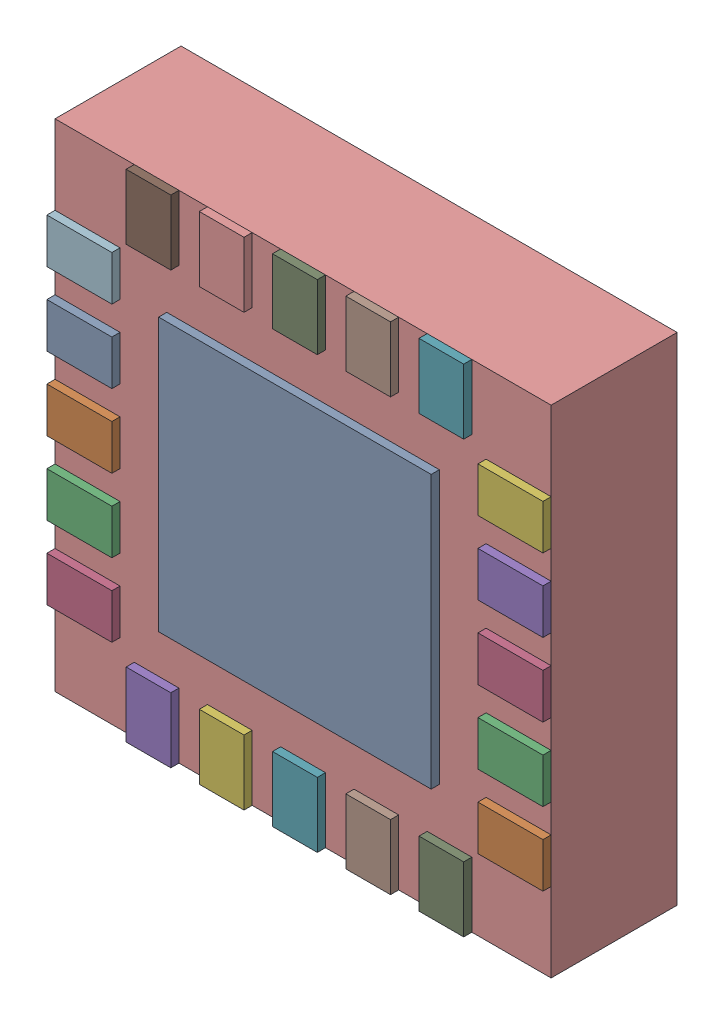
SolidWorks assembly U4, configuration Default. Lengths in mm.
Overall size (3.1 3.1 0.84).
24 component instances, 23 part files, 0 mates.
Components (placement in the parent):
- U4-subassembly-1-1: U4-subassembly-1 [Default] at (0.0001 0 -1.6307) x (0 1 0) z (0 0 -1) size (3.1 3.1 0.84)
  - VQFN20_3X3_MCH-1: VQFN20_3X3_MCH [Default] at origin size (1.7 1.7 0.05)
  - VQFN20_3X3_MCH-1-1: VQFN20_3X3_MCH-1 [Default] at origin size (0.28 0.41 0.05)
  - VQFN20_3X3_MCH-2-1: VQFN20_3X3_MCH-2 [Default] at origin size (0.28 0.41 0.05)
  - VQFN20_3X3_MCH-3-1: VQFN20_3X3_MCH-3 [Default] at origin size (0.28 0.41 0.05)
  - VQFN20_3X3_MCH-4-1: VQFN20_3X3_MCH-4 [Default] at origin size (0.28 0.41 0.05)
  - VQFN20_3X3_MCH-5-1: VQFN20_3X3_MCH-5 [Default] at origin size (0.28 0.41 0.05)
  - VQFN20_3X3_MCH-6-1: VQFN20_3X3_MCH-6 [Default] at origin size (0.41 0.28 0.05)
  - VQFN20_3X3_MCH-7-1: VQFN20_3X3_MCH-7 [Default] at origin size (0.41 0.28 0.05)
  - VQFN20_3X3_MCH-8-1: VQFN20_3X3_MCH-8 [Default] at origin size (0.41 0.28 0.05)
  - VQFN20_3X3_MCH-9-1: VQFN20_3X3_MCH-9 [Default] at origin size (0.41 0.28 0.05)
  - VQFN20_3X3_MCH-10-1: VQFN20_3X3_MCH-10 [Default] at origin size (0.41 0.28 0.05)
  - VQFN20_3X3_MCH-11-1: VQFN20_3X3_MCH-11 [Default] at origin size (0.28 0.41 0.05)
  - VQFN20_3X3_MCH-12-1: VQFN20_3X3_MCH-12 [Default] at origin size (0.28 0.41 0.05)
  - VQFN20_3X3_MCH-13-1: VQFN20_3X3_MCH-13 [Default] at origin size (0.28 0.41 0.05)
  - VQFN20_3X3_MCH-14-1: VQFN20_3X3_MCH-14 [Default] at origin size (0.28 0.41 0.05)
  - VQFN20_3X3_MCH-15-1: VQFN20_3X3_MCH-15 [Default] at origin size (0.28 0.41 0.05)
  - VQFN20_3X3_MCH-16-1: VQFN20_3X3_MCH-16 [Default] at origin size (0.41 0.28 0.05)
  - VQFN20_3X3_MCH-17-1: VQFN20_3X3_MCH-17 [Default] at origin size (0.41 0.28 0.05)
  - VQFN20_3X3_MCH-18-1: VQFN20_3X3_MCH-18 [Default] at origin size (0.41 0.28 0.05)
  - VQFN20_3X3_MCH-19-1: VQFN20_3X3_MCH-19 [Default] at origin size (0.41 0.28 0.05)
  - VQFN20_3X3_MCH-20-1: VQFN20_3X3_MCH-20 [Default] at origin size (0.41 0.28 0.05)
  - VQFN20_3X3_MCH-21-1: VQFN20_3X3_MCH-21 [Default] at origin size (3.1 3.1 0.79)
  - VQFN20_3X3_MCH-22-1: VQFN20_3X3_MCH-22 [Default] at origin size (0.15 0.15 0)
